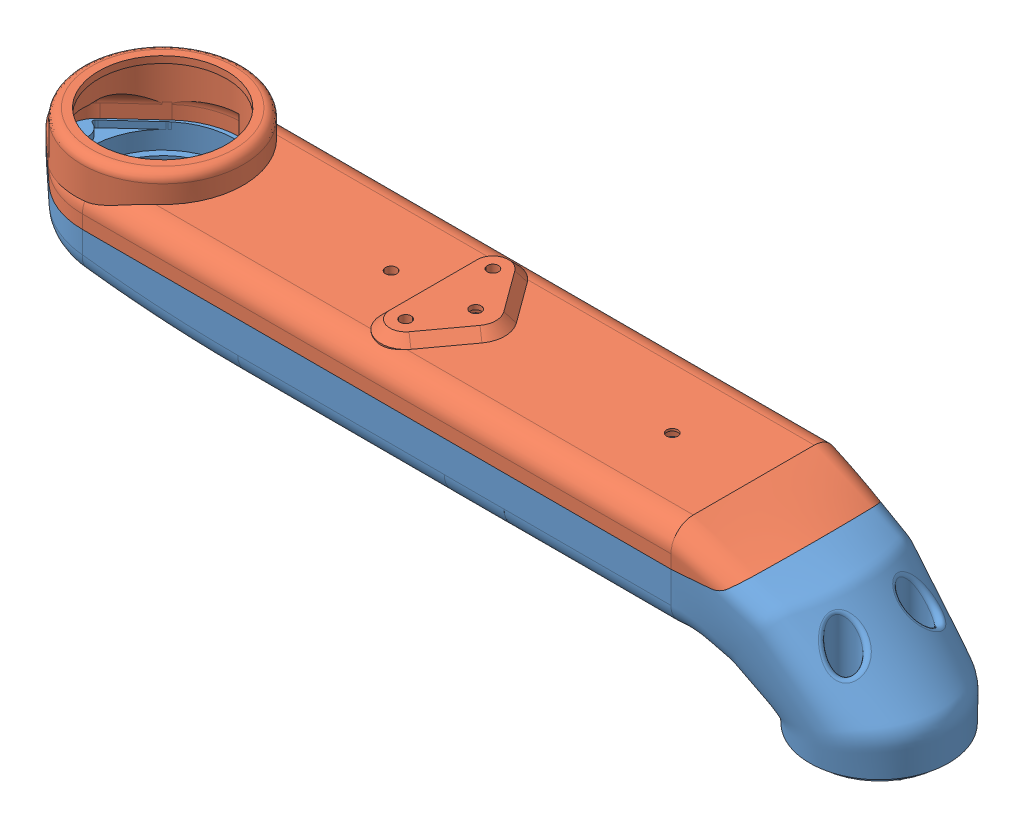
SolidWorks assembly upper leg module_v2, configuration Default. Lengths in mm.
Overall size (198.25 43.5 37.06).
2 component instances, 2 part files, 3 mates.
Components (placement in the parent):
- upper leg module shell base-1: upper leg module shell base [Default] at (64.5696 101.4754 134.999) x (0 0 1) z (-1 0 0) size (37.02 37.51 198.25)
- upper leg module cover-1: upper leg module cover [Default] at (58.1988 107.4754 134.999) size (170.23 17.96 37.06)
Mates (geometry in assembly coordinates):
- Coincident1: coincident anti-aligned: plane of upper leg module shell base-1 through (24.5696 107.4754 153.499) normal (0 1 0); plane of upper leg module cover-1 through (58.1988 107.4754 134.999) normal (0 -1 0)
- Coincident2: coincident: line of upper leg module shell base-1 through (4.1397 107.4754 153.499) axis (1 0 0); plane of upper leg module cover-1 through (135.5688 115.4754 153.499) normal (0 0 1)
- Coincident4: coincident anti-aligned: plane of upper leg module shell base-1 through (95.0825 65.1116 116.4949) normal (-0.642788 0.766044 0); plane of upper leg module cover-1 through (94.2983 64.4537 116.449) normal (0.642788 -0.766044 0)
